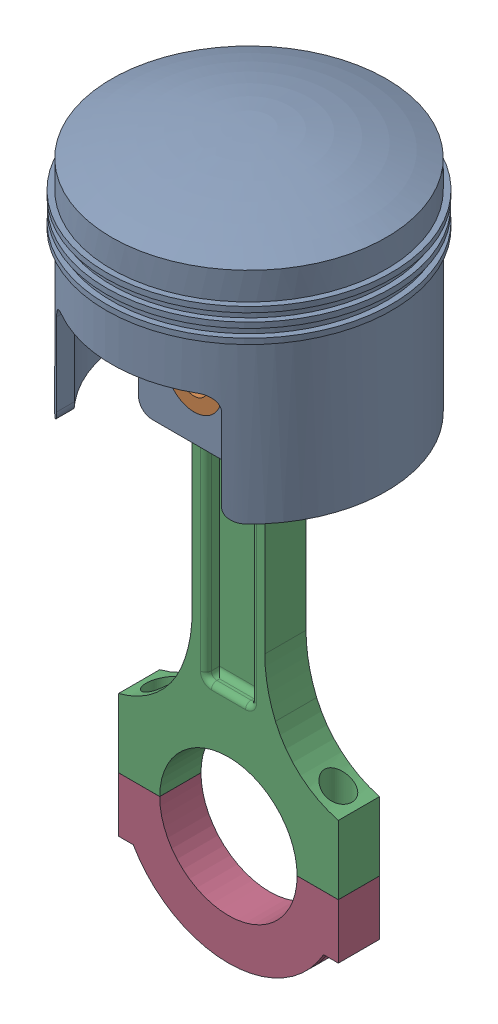
SolidWorks assembly piston_sys, configuration Default. Lengths in mm.
Overall size (104 260.01 104).
4 component instances, 4 part files, 5 mates.
Components (placement in the parent):
- piston-1: piston [Default] at (36.9808 2.9936 88.4626) size (104 90 104)
- wrist_pin-1: wrist_pin [Default] at (36.9808 22.9936 108.4626) x (-0.988472 -0.151404 0) z (0 0 1) size (20 20 40)
- connecting_rod-1: connecting_rod [Default] at (36.9808 22.9936 88.4275) x (1 -0.000128 0) z (0 0 1) size (80 170 15)
- piston_cap-3: piston_cap [Default] at (36.9617 -127.0156 80.9275) x (1 -0.000128 0) z (0 0 1) size (80 40 15)
Mates (geometry in assembly coordinates):
- Concentric1: concentric aligned: cylinder of piston-1 through (36.9808 22.9936 36.4626) axis (0 0 1) radius 10; cylinder of wrist_pin-1 through (36.9808 22.9936 68.4626) axis (0 0 1) radius 10
- Concentric2: concentric aligned: cylinder of piston-1 through (36.9808 22.9936 36.4626) axis (0 0 1) radius 10; cylinder of wrist_pin-1 through (36.9808 22.9936 68.4626) axis (0 0 1) radius 10
- Coincident1: coincident aligned: circle of piston-1; plane of wrist_pin-1 through (36.9808 22.9936 108.4626) normal (0 0 1)
- Concentric5: concentric aligned: cylinder of wrist_pin-1 through (36.9808 22.9936 68.4626) axis (0 0 1) radius 10; cylinder of connecting_rod-1 through (36.9808 22.9936 88.4275) axis (0 0 1) radius 10
- Concentric6: concentric anti-aligned: cylinder of connecting_rod-1 through (4.4834 42.9978 88.4275) axis (-0.000128 -1 0) radius 5; cylinder of piston_cap-3 through (4.4565 -167.0114 88.4275) axis (0.000128 1 0) radius 5
